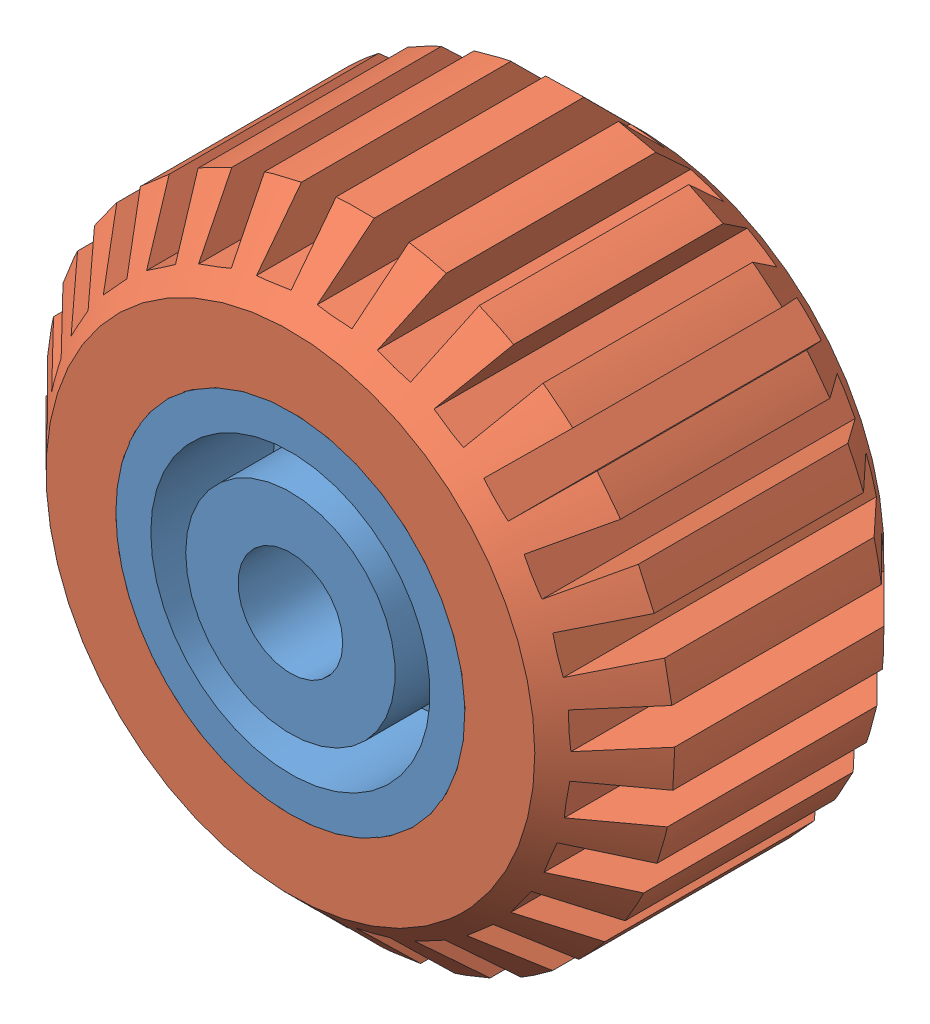
SolidWorks assembly Assem1, configuration Default. Lengths in mm.
Overall size (25.44 25.44 10).
2 component instances, 2 part files, 2 mates.
Components (placement in the parent):
- Part6-1: Part6 [Default] at origin size (10 10 10)
- Part7-2: Part7 [Default] at (0 0 -5) x (0.697936 -0.71616 0) z (0 0 1) size (18 17.99 10)
Mates (geometry in assembly coordinates):
- Concentric1: concentric aligned: cylinder of Part6-1 through (0 0 0) axis (0 0 -1) radius 5; cylinder of Part7-2 through (0 0 5) axis (0 0 -1) radius 5
- Coincident1: coincident aligned: plane of Part6-1 through (0 4 5) normal (0 0 1); plane of Part7-2 through (0 0 5) normal (0 0 1)
